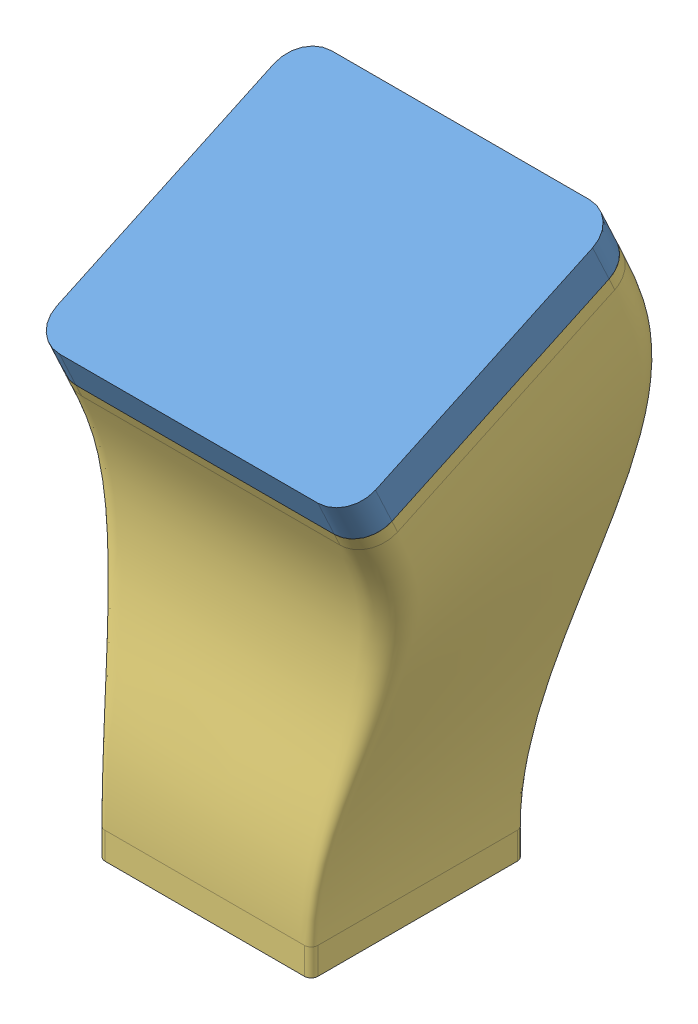
SolidWorks assembly tower-assembly, configuration Default. Lengths in mm.
Overall size (47.6 95.99 92.97).
3 component instances, 3 part files, 8 mates.
Components (placement in the parent):
- nfc-tower-top-1: nfc-tower-top [Default] at (0 71.8208 29.5075) x (1 0 0) z (0 -0.422618 0.906308) size (47.5 5.8 44.7)
- nfc-module-1: nfc-module [Default] at (0 72.999 30.0569) x (-1 0 0) z (0 -0.422618 0.906308) size (42.85 3.45 40.6)
- nfc-tower-bottom-1: nfc-tower-bottom [Default] at (0 71.8208 29.5075) x (-1 0 0) z (0 -0.906308 -0.422618) size (47.6 69.63 70.67)
Mates (geometry in assembly coordinates):
- Coincident1: coincident anti-aligned: plane of nfc-tower-top-1 through (-19.25 65.4553 46.2345) normal (0 -0.906308 -0.422618); plane of nfc-module-1 through (-19.425 65.2651 46.6424) normal (0 0.906308 0.422618)
- Width1: width aligned: plane of nfc-module-1 through (19.425 80.5359 11.1729) normal (0 0.422618 -0.906308); plane of nfc-module-1 through (19.425 63.3776 47.969) normal (0 -0.422618 0.906308); plane of nfc-tower-top-1 through (0 64.3987 48.5003) normal (0 0.422618 -0.906308); plane of nfc-tower-top-1 through (0 81.5993 11.6136) normal (0 -0.422618 0.906308)
- Width2: width anti-aligned: plane of nfc-tower-top-1 through (21.75 72.999 30.0569) normal (-1 0 0); plane of nfc-tower-top-1 through (-21.75 72.999 30.0569) normal (1 0 0); plane of nfc-module-1 through (21.425 79.6907 12.9855) normal (1 0 0); plane of nfc-module-1 through (-21.425 79.6907 12.9855) normal (-1 0 0)
- InPlace1: in place: plane of assembly through (0 0 0) normal (0 -1 0); plane of ? through (0 0 0) normal (0 -1 0); moOrthogonalPlaneRef_w of assembly through (0 0 0) normal (0 -1 0); unknown of ?; plane of assembly through (0 0 0) normal (0 -1 0); line of ? through (55 -55 0) axis (0 0 -1); plane of nfc-tower-top-1 through (0 71.8208 29.5075) normal (0 -0.906308 -0.422618); unknown of nfc-tower-bottom-1
- Coincident2: coincident aligned: plane of nfc-tower-top-1; plane of nfc-tower-bottom-1
- Coincident3: coincident aligned: moOrthogonalPlaneRef_w of nfc-tower-top-1; plane of nfc-tower-bottom-1
- Coincident4: coincident anti-aligned: moOrthogonalPlaneRef_w of nfc-tower-top-1 through (0 71.8208 29.5075) normal (1 0 0); plane of nfc-tower-bottom-1
- Coincident6: coincident anti-aligned: plane of nfc-tower-bottom-1 through (0 0 29.5075) normal (0 -1 0); plane of assembly through (0 0 0) normal (0 1 0)
